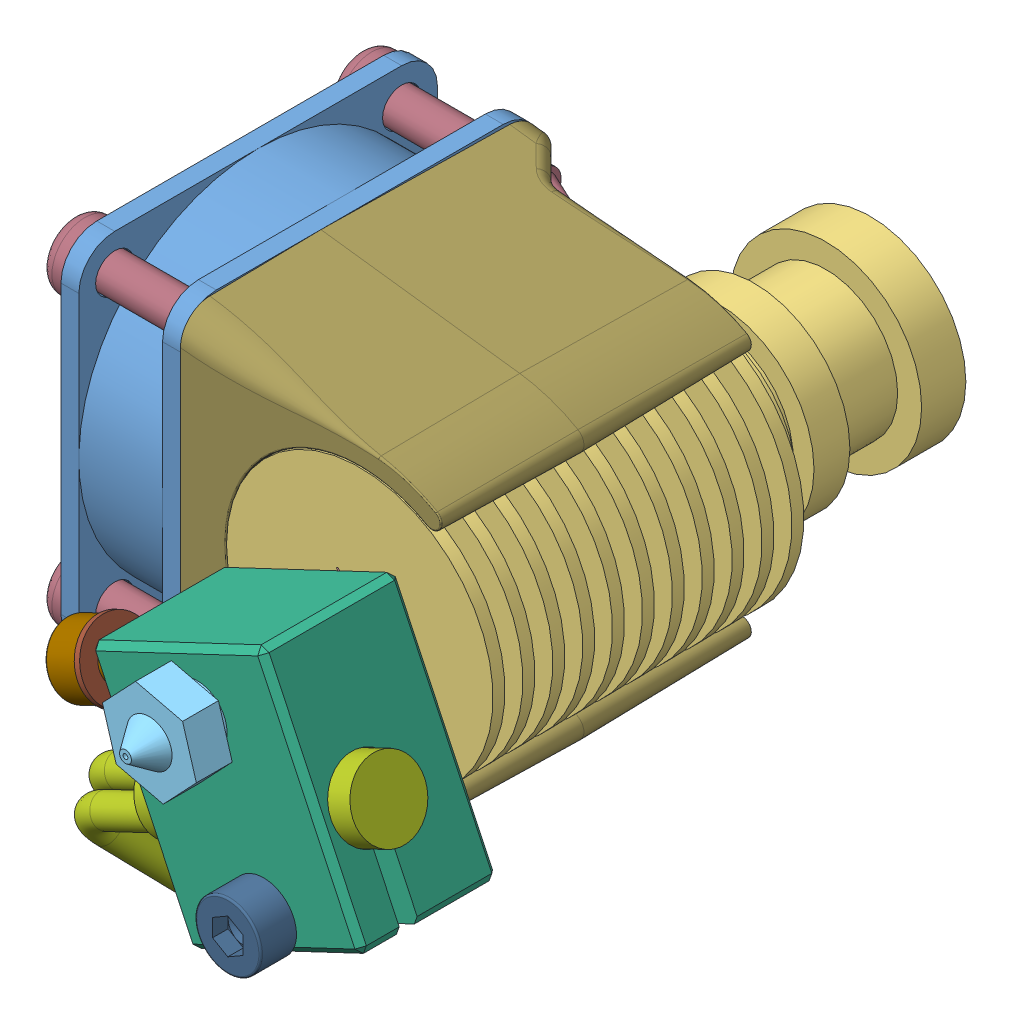
SolidWorks assembly E3D All Metal Hotend V6 assy, configuration Default. Lengths in mm.
Overall size (43.11 41.55 62.3).
17 component instances, 13 part files, 17 mates.
Components (placement in the parent):
- Fan-DC-KDE0503PFB3-Promoco-1: Fan-DC-KDE0503PFB3-Promoco [Default] at (-15 0 -15) x (0 0 -1) z (-1 0 0) size (30 30 10)
  - Fan-House-30x30x10-Promoco(Fan-House-KDE0503PFB3-Promoco)-1: Fan-House-30x30x10-Promoco(Fan-House-KDE0503PFB3-Promoco) [Default] at origin size (30 30 10)
  - Fan-30x30x10-Promoco(Fan-KDE0503PFB3-Promoco)-1: Fan-30x30x10-Promoco(Fan-KDE0503PFB3-Promoco) [Default] x (0 0 -1) z (-0.999131 0.04169 0) size (8.5 27.91 28)
- E3D v6 HotEnd - Heatsink-1: E3D v6 HotEnd - Heatsink [Default] at origin size (22.3 22.3 42.7)
- E3D v6 HotEnd - Heatbreak-1: E3D v6 HotEnd - Heatbreak [Default] at (0 0 7.1) x (0.951461 0.30777 0) z (0 0 1) size (7 7 21.9)
- E3D v6 HotEnd - Nozzle(ÃÞÌ«ÙÄ)-1: E3D v6 HotEnd - Nozzle(ÃÞÌ«ÙÄ) [Default] at (0 0 17.6) x (0.686854 0.726796 0) z (0 0 1) size (8.08 7 12.5)
- E3D v6 HotEnd - Heat Block-1: E3D v6 HotEnd - Heat Block [Default] at (-0.6002 -17.4324 13.6) x (-0.427793 0.903877 0) z (-0.903877 -0.427793 0) size (20 11.5 16)
- Ceramic Cartridge Heater-1: Ceramic Cartridge Heater [Default] at (-6.0442 -10.6051 9.6) x (-0.28175 0.595306 -0.752481) z (-0.903877 -0.427793 0) size (6 18 29.25)
- Thermistor-1: Thermistor [Default] at (-4.3686 0.6982 11.6) x (-0.401994 0.849366 0.34202) z (0.903877 0.427793 0) size (4.52 1.5 4.65)
- HEXAGON SOCKET HEAD CAP SCREWS(SCB3-4)-1: HEXAGON SOCKET HEAD CAP SCREWS(SCB3-4) [Default] at (-9.0236 -1.5049 11.6) x (-0.427595 0.903459 0.030402) z (-0.903877 -0.427793 0) size (5.5 5.5 7)
- HEXAGON SOCKET HEAD CAP SCREWS(SCB3-10)-1: HEXAGON SOCKET HEAD CAP SCREWS(SCB3-10) [Default] at (5.5613 -11.7504 13.6) size (5.5 5.5 13)
- Flat Washers(PWF3)-1: Flat Washers(PWF3) [Default] at (-9.0236 -1.5049 11.6) x (-0.427793 0.903877 0) z (-0.903877 -0.427793 0) size (6 6 0.5)
- E3D-v6 Fan Duct-1: E3D-v6 Fan Duct [Default] x (1 0 0) z (0 1 0) size (22.31 30.18 30)
- Self Tapping Screws - Pan Head(CSPTRSA-SUS-TP3-16)-1: Self Tapping Screws - Pan Head(CSPTRSA-SUS-TP3-16) [Default] at (-25 12 -3) size (18.01 5.5 5.5)
- Self Tapping Screws - Pan Head(CSPTRSA-SUS-TP3-16)-2: Self Tapping Screws - Pan Head(CSPTRSA-SUS-TP3-16) [Default] at (-25 -12 -27) size (18.01 5.5 5.5)
- Self Tapping Screws - Pan Head(CSPTRSA-SUS-TP3-16)-3: Self Tapping Screws - Pan Head(CSPTRSA-SUS-TP3-16) [Default] at (-25 12 -27) size (18.01 5.5 5.5)
- Self Tapping Screws - Pan Head(CSPTRSA-SUS-TP3-16)-4: Self Tapping Screws - Pan Head(CSPTRSA-SUS-TP3-16) [Default] at (-25 -12 -3) size (18.01 5.5 5.5)
Mates (geometry in assembly coordinates):
- Concentric1: concentric aligned: cylinder of E3D v6 HotEnd - Heatsink-1 through (0 0 0) axis (0 0 1) radius 3; cylinder of E3D v6 HotEnd - Heatbreak-1 through (0 0 7.1) axis (0 0 1) radius 3.5
- Coincident1: coincident aligned: plane of E3D v6 HotEnd - Heatsink-1 through (0 0 0) normal (0 0 1); plane of E3D v6 HotEnd - Heatbreak-1 through (-1.0772 3.3301 0) normal (0 0 1)
- Concentric2: concentric anti-aligned: cylinder of E3D v6 HotEnd - Heatbreak-1 through (0 0 7.1) axis (0 0 1) radius 3; cylinder of E3D v6 HotEnd - Heat Block-1 through (0 0 2.1) axis (0 0 -1) radius 2.5
- Coincident2: coincident aligned: plane of E3D v6 HotEnd - Heatbreak-1 through (-1.0772 3.3301 2.1) normal (0 0 -1); plane of E3D v6 HotEnd - Heat Block-1 through (-0.6002 -17.4324 2.1) normal (0 0 -1)
- Concentric3: concentric aligned: cylinder of E3D v6 HotEnd - Nozzle(ÃÞÌ«ÙÄ)-1 through (0 0 17.6) axis (0 0 -1) radius 3; cylinder of E3D v6 HotEnd - Heat Block-1 through (0 0 2.1) axis (0 0 -1) radius 2.5
- Coincident3: coincident anti-aligned: plane of E3D v6 HotEnd - Heatbreak-1 through (-1.0772 3.3301 7.1) normal (0 0 1); plane of E3D v6 HotEnd - Nozzle(ÃÞÌ«ÙÄ)-1 through (0 0 7.1) normal (0 0 -1)
- Concentric4: concentric aligned: circle of E3D v6 HotEnd - Heat Block-1; cylinder of HEXAGON SOCKET HEAD CAP SCREWS(SCB3-10)-1 through (5.5613 -11.7504 16.6) axis (0 0 1) radius 1.5
- Coincident5: coincident anti-aligned: plane of E3D v6 HotEnd - Heat Block-1 through (-0.6002 -17.4324 13.6) normal (0 0 1); plane of HEXAGON SOCKET HEAD CAP SCREWS(SCB3-10)-1 through (5.5613 -9.0004 13.6) normal (0 0 -1)
- Concentric5: concentric aligned: cylinder of E3D v6 HotEnd - Heat Block-1 through (-8.3005 -1.1627 11.6) axis (-0.903877 -0.427793 0) radius 1; cylinder of Thermistor-1 through (-4.3686 0.6982 11.6) axis (-0.903877 -0.427793 0) radius 0.75
- Coincident6: coincident anti-aligned: plane of E3D v6 HotEnd - Heat Block-1 through (-0.6002 -17.4324 2.1) normal (-0.903877 -0.427793 0); plane of Thermistor-1 through (-8.1727 -1.4328 10.9591) normal (0.903877 0.427793 0)
- Angle1: planar angle = 0.349066 rad aligned: plane of Thermistor-1 through (-6.1635 -0.1845 12.1211) normal (0.146314 -0.309144 0.939693); plane of E3D v6 HotEnd - Heat Block-1 through (-0.6002 -17.4324 13.6) normal (0 0 1)
- Concentric6: concentric aligned: cylinder of E3D v6 HotEnd - Heat Block-1 through (-8.3005 -1.1627 11.6) axis (-0.903877 -0.427793 0) radius 1; cylinder of Flat Washers(PWF3)-1 through (-9.0236 -1.5049 11.6) axis (-0.903877 -0.427793 0) radius 1.6
- Concentric7: concentric aligned: cylinder of E3D v6 HotEnd - Heat Block-1 through (-8.3005 -1.1627 11.6) axis (-0.903877 -0.427793 0) radius 1; cylinder of HEXAGON SOCKET HEAD CAP SCREWS(SCB3-4)-1 through (-11.7352 -2.7883 11.6) axis (-0.903877 -0.427793 0) radius 1.5
- Coincident8: coincident anti-aligned: plane of Thermistor-1 through (-8.3999 -1.6538 11.2411) normal (-0.903877 -0.427793 0); plane of Flat Washers(PWF3)-1 through (-8.5717 -1.291 10) normal (0.903877 0.427793 0)
- Coincident9: coincident anti-aligned: plane of HEXAGON SOCKET HEAD CAP SCREWS(SCB3-4)-1 through (-9.0594 -1.4293 8.8513) normal (0.903877 0.427793 0); plane of Flat Washers(PWF3)-1 through (-9.0236 -1.5049 10) normal (-0.903877 -0.427793 0)
- Concentric8: concentric anti-aligned: cylinder of E3D v6 HotEnd - Heat Block-1 through (10.2256 -2.9048 9.6) axis (-0.903877 -0.427793 0) radius 3.05; cylinder of Ceramic Cartridge Heater-1 through (-6.0442 -10.6051 9.6) axis (0.903877 0.427793 0) radius 3
- Distance1: distance = 2 mm aligned: plane of Ceramic Cartridge Heater-1 through (-6.0442 -10.6051 9.6) normal (-0.903877 -0.427793 0); plane of E3D v6 HotEnd - Heat Block-1 through (-0.6002 -17.4324 2.1) normal (-0.903877 -0.427793 0)
